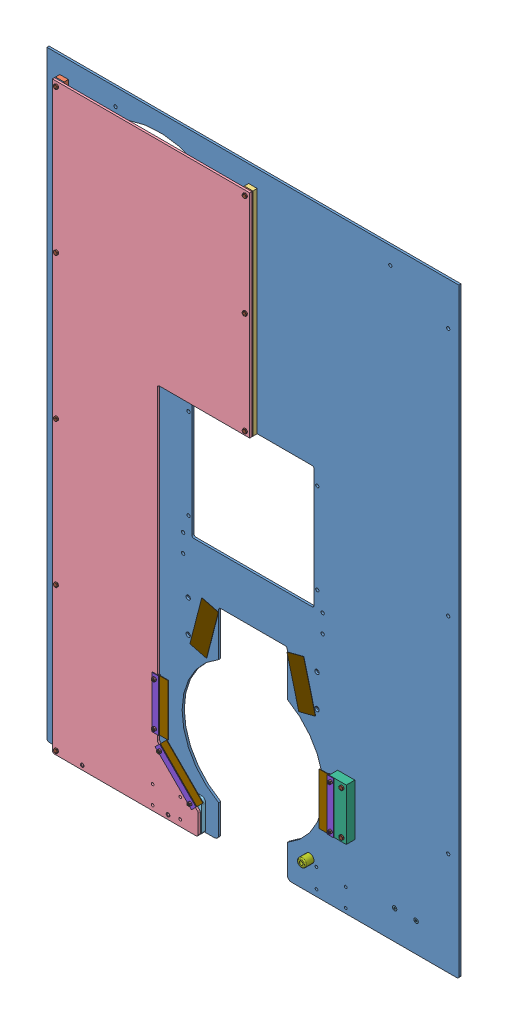
SolidWorks assembly GE-19137, configuration Default. Lengths in mm.
Overall size (1219.2 1778 85.73).
70 component instances, 22 part files, 140 mates.
Components (placement in the parent):
- GE-19131-1: GE-19131 [Default] at origin size (1219.2 1778 6.35)
- GE-19134-1: GE-19134 [Default] at (38.1 0 6.35) size (25.4 1727.2 12.7)
- GE-19135-1: GE-19135 [Default] at (622.3 1098.55 6.35) size (25.4 628.65 12.7)
- GE-19133-2: GE-19133 [Default] at (38.1 0 22.225) size (584.2 1727.2 6.35)
- GE-19138-1: GE-19138 [Default] at (0 0 6.35) size (406.4 120.65 12.7)
- GE-19139-2: GE-19139 [Default] at (1216.025 38.1 31.75) x (-1 0 0) z (0 0 -1) size (50.8 152.4 25.4)
- GE-19140-1: GE-19140 [Default] at (777.6052 88.9 6.35) x (-1 0 0) z (0 0 1) size (25.4 25.4 25.4)
- GE-19190-1: GE-19190 [Default] at (838.1961 325.1694 81.6653) x (0 0 1) z (0 -1 0) size (6.35 44.45 152.4)
  - GE-19190-1-1: GE-19190-1 [Default] at (-48.3278 -36.5164 -30.4306) size (6.35 19.05 152.4)
  - GE-19190-2-1: GE-19190-2 [Default] at (-50.709 -46.4642 60.9432) x (0 0 1) z (-1 0 0) size (152.4 28.57 3.17)
- GE-19190-2: GE-19190 [Default] at (371.4789 233.6306 78.4903) x (0 0 1) z (0 1 0) size (6.35 44.45 152.4)
  - GE-19190-1-1: GE-19190-1 [Default] at (-48.3278 -36.5164 -30.4306) size (6.35 19.05 152.4)
  - GE-19190-2-1: GE-19190-2 [Default] at (-50.709 -46.4642 60.9432) x (0 0 1) z (-1 0 0) size (152.4 28.57 3.17)
- GE-19190-3: GE-19190 [Default] at (455.8906 108.9458 78.4903) x (0 0 1) z (-0.707107 0.707107 0) size (6.35 44.45 152.4)
  - GE-19190-1-1: GE-19190-1 [Default] at (-48.3278 -36.5164 -30.4306) size (6.35 19.05 152.4)
  - GE-19190-2-1: GE-19190-2 [Default] at (-50.709 -46.4642 60.9432) x (0 0 1) z (-1 0 0) size (152.4 28.57 3.17)
- GE-19142-1: GE-19142 [Default] at (114.3 63.5 0) size (88.9 44.45 44.45)
- GE-19142-2: GE-19142 [Default] at (1016 63.5 0) size (88.9 44.45 44.45)
- hex_.25_20_1.5-1: hex_.25_20_1.5 [92865A546] at (50.8 1714.5 11.5094) x (0 0 -1) z (-1 0 0) size (42.07 12.83 11.11)
- hex_.25_20_1.5-2: hex_.25_20_1.5 [92865A546] at (50.8 1289.05 11.5094) x (0 0 -1) z (-0.987351 -0.158553 0) size (42.07 12.83 11.11)
- hex_.25_20_1.5-3: hex_.25_20_1.5 [92865A546] at (50.8 863.6 11.5094) x (0 0 -1) z (-0.959125 -0.282984 0) size (42.07 12.83 11.11)
- hex_.25_20_1.5-4: hex_.25_20_1.5 [92865A546] at (50.8 438.15 11.5094) x (0 0 -1) z (-0.928571 -0.371154 0) size (42.07 12.83 11.11)
- hex_.25_20_1.5-5: hex_.25_20_1.5 [92865A546] at (50.8 12.7 11.5094) x (0 0 -1) z (-0.906989 -0.421154 0) size (42.07 12.83 11.11)
- hex_.25_20_1.5-8: hex_.25_20_1.5 [92865A546] at (898.525 342.9 14.6844) x (0 0 -1) z (-0.985697 -0.168526 0) size (42.07 12.83 11.11)
- hex_.25_20_1.5-9: hex_.25_20_1.5 [92865A546] at (898.525 215.9 14.6844) x (0 0 -1) z (-1 0 0) size (42.07 12.83 11.11)
- hex_.25_20_1.5-10: hex_.25_20_1.5 [92865A546] at (609.6 1714.5 11.5094) x (0 0 -1) z (-0.985697 0.168526 0) size (42.07 12.83 11.11)
- hex_.25_20_1.5-11: hex_.25_20_1.5 [92865A546] at (609.6 1412.875 11.5094) x (0 0 -1) z (-0.952324 0.305088 0) size (42.07 12.83 11.11)
- hex_.25_20_1.5-12: hex_.25_20_1.5 [92865A546] at (609.6 1111.25 11.5094) x (0 0 -1) z (-0.919615 0.39282 0) size (42.07 12.83 11.11)
- nylock_.25_20-1: nylock_.25_20 [Default] at (50.8 1714.5 0) x (-1 0 0) z (0 -1 0) size (11.11 7.94 12.83)
- nylock_.25_20-2: nylock_.25_20 [Default] at (50.8 1289.05 0) x (-0.987351 -0.158553 0) z (0.158553 -0.987351 0) size (11.11 7.94 12.83)
- nylock_.25_20-3: nylock_.25_20 [Default] at (50.8 863.6 0) x (-0.959125 -0.282984 0) z (0.282984 -0.959125 0) size (11.11 7.94 12.83)
- nylock_.25_20-4: nylock_.25_20 [Default] at (50.8 438.15 0) x (-0.928571 -0.371154 0) z (0.371154 -0.928571 0) size (11.11 7.94 12.83)
- nylock_.25_20-5: nylock_.25_20 [Default] at (50.8 12.7 0) x (-0.906989 -0.421154 0) z (0.421154 -0.906989 0) size (11.11 7.94 12.83)
- nylock_.25_20-8: nylock_.25_20 [Default] at (609.6 1714.5 0) x (-0.952324 -0.305088 0) z (0.305088 -0.952324 0) size (11.11 7.94 12.83)
- nylock_.25_20-9: nylock_.25_20 [Default] at (609.6 1412.875 0) x (-0.985697 -0.168526 0) z (0.168526 -0.985697 0) size (11.11 7.94 12.83)
- nylock_.25_20-10: nylock_.25_20 [Default] at (609.6 1111.25 0) x (-1 0 0) z (0 -1 0) size (11.11 7.94 12.83)
- nylock_.25_20-11: nylock_.25_20 [Default] at (898.525 342.9 0) x (-0.985697 0.168526 0) z (-0.168526 -0.985697 0) size (11.11 7.94 12.83)
- nylock_.25_20-12: nylock_.25_20 [Default] at (898.525 215.9 0) x (-0.952324 0.305088 0) z (-0.305088 -0.952324 0) size (11.11 7.94 12.83)
- nylock_10_32-7: nylock_10_32 [90631A411] at (342.9 342.9 30.1625) x (-0.98095 0.194258 0) z (0.194258 0.98095 0) size (9.53 5.95 11)
- nylock_10_32-8: nylock_10_32 [90631A411] at (342.9 215.9 30.1625) x (-0.999342 0.036269 0) z (0.036269 0.999342 0) size (9.53 5.95 11)
- nylock_10_32-3: nylock_10_32 [90631A411] at (358.4172 166.0026 30.1625) x (-0.995826 -0.091275 0) z (-0.091275 0.995826 0) size (9.53 5.95 11)
- nylock_10_32-4: nylock_10_32 [90631A411] at (448.2197 76.2 30.1625) x (-0.982982 -0.183701 0) z (-0.183701 0.982982 0) size (9.53 5.95 11)
- nylock_10_32-9: nylock_10_32 [90631A411] at (866.775 342.9 33.3375) x (-0.971524 -0.236941 0) z (-0.236941 0.971524 0) size (9.53 5.95 11)
- nylock_10_32-6: nylock_10_32 [90631A411] at (866.775 215.9 33.3375) x (-0.969173 -0.24638 0) z (-0.24638 0.969173 0) size (9.53 5.95 11)
- nylock_.25_20-13: nylock_.25_20 [Default] at (1092.2 85.725 -1.9812) x (0.972777 -0.231744 0) z (0.231744 0.972777 0) size (11.11 7.94 12.83)
- nylock_.25_20-14: nylock_.25_20 [Default] at (1028.7 85.725 -1.9812) x (0.994367 -0.105992 0) z (0.105992 0.994367 0) size (11.11 7.94 12.83)
- nylock_.25_20-15: nylock_.25_20 [Default] at (190.5 85.725 -1.9812) x (0.999918 -0.012843 0) z (0.012843 0.999918 0) size (11.11 7.94 12.83)
- nylock_.25_20-16: nylock_.25_20 [Default] at (127 85.725 -1.9812) x (0.999134 0.04161 0) z (-0.04161 0.999134 0) size (11.11 7.94 12.83)
- flat_hex_.25_20_1-1: flat_hex_.25_20_1 [91253A542] at (1028.7 85.725 6.35) x (-1 0 0) z (0 0 1) size (13.49 13.49 25.61)
- flat_hex_.25_20_1-2: flat_hex_.25_20_1 [91253A542] at (1092.2 85.725 6.35) x (-0.987351 -0.158553 0) z (0 0 1) size (13.49 13.49 25.61)
- flat_hex_.25_20_1-3: flat_hex_.25_20_1 [91253A542] at (127 85.725 6.35) x (-0.959125 -0.282984 0) z (0 0 1) size (13.49 13.49 25.61)
- flat_hex_.25_20_1-4: flat_hex_.25_20_1 [91253A542] at (190.5 85.725 6.35) x (-0.928571 -0.371154 0) z (0 0 1) size (13.49 13.49 25.61)
- nylock_.25_20-17: nylock_.25_20 [Default] at (777.6052 88.9 0) x (0.972777 -0.231744 0) z (0.231744 0.972777 0) size (11.11 7.94 12.83)
- button_hex_.25_20_1.25-1: button_hex_.25_20_1.25 [Default] at (777.6052 88.9 22.4028) size (11.1 11.1 35.11)
- flat_hex_10_32_.625-1: flat_hex_10_32_.625 [Default] at (342.9 342.9 22.225) x (-0.923728 -0.383049 0) z (0 0 -1) size (10.44 10.44 15.88)
- flat_hex_10_32_.625-2: flat_hex_10_32_.625 [Default] at (342.9 215.9 22.225) x (-0.85131 -0.524663 0) z (0 0 -1) size (10.44 10.44 15.88)
- flat_hex_10_32_.625-3: flat_hex_10_32_.625 [Default] at (358.4172 166.0026 22.225) x (-0.777574 -0.628792 0) z (0 0 -1) size (10.44 10.44 15.88)
- flat_hex_10_32_.625-4: flat_hex_10_32_.625 [Default] at (448.2197 76.2 22.225) x (-0.715577 -0.698533 0) z (0 0 -1) size (10.44 10.44 15.88)
- flat_hex_10_32_1.375-1: flat_hex_10_32_1.375 [Default] at (866.775 342.9 6.35) x (-0.923728 -0.383049 0) z (0 0 -1) size (10.44 10.44 34.93)
- flat_hex_10_32_1.375-2: flat_hex_10_32_1.375 [Default] at (866.775 215.9 6.35) x (-0.85131 -0.524663 0) z (0 0 -1) size (10.44 10.44 34.93)
- VisionTape-1: VisionTape [Default] at (423.8881 461.6361 6.35) x (0.968246 -0.25 0) z (0 0 1) size (50.8 139.7 0.79)
- VisionTape-2: VisionTape [Default] at (746.125 448.9361 6.35) x (0.968246 0.25 0) z (0 0 1) size (50.8 139.7 0.79)
- GE-19251-1: GE-19251 [Default] at (38.1 0 19.05) size (25.4 1727.2 3.17)
- GE-19252-1: GE-19252 [Default] at (622.3 1098.55 19.05) size (25.4 628.65 3.17)
- GE-19253-1: GE-19253 [92805K33] at (127 12.7 3.175) x (1 0 0) z (0 -1 0) size (7.81 25.4 7.81)
- GE-19253-2: GE-19253 [92805K33] at (381 12.7 3.175) x (1 0 0) z (0 -1 0) size (7.81 25.4 7.81)
- nylock_10_32-10: nylock_10_32 [90631A411] at (127 12.7 0) x (-0.923728 -0.383049 0) z (0.383049 -0.923728 0) size (9.53 5.95 11)
- nylock_10_32-11: nylock_10_32 [90631A411] at (381 12.7 0) x (1 0 0) z (0 1 0) size (9.53 5.95 11)
- round_hex_flange_10_32_1.5_partial-1: round_hex_flange_10_32_1.5_partial [Default] at (127 12.7 31.1404) size (10.34 10.34 40.67)
- round_hex_flange_10_32_1.5_partial-2: round_hex_flange_10_32_1.5_partial [Default] at (381 12.7 31.1404) size (10.34 10.34 40.67)
Mates (geometry in assembly coordinates):
- Coincident1: coincident: plane of GE-19131-1 through (0 0 6.35) normal (0 0 1); plane of GE-19134-1 through (38.1 0 6.35) normal (0 0 -1)
- Concentric1: concentric: cylinder of GE-19131-1 through (50.8 12.7 0) axis (0 0 1) radius 3.3655; cylinder of GE-19134-1 through (50.8 12.7 6.35) axis (0 0 1) radius 3.3655
- Coincident2: coincident: plane of GE-19131-1 through (0 0 6.35) normal (0 0 1); plane of GE-19135-1 through (622.3 1098.55 6.35) normal (0 0 -1)
- Concentric2: concentric: cylinder of GE-19131-1 through (609.6 1111.25 0) axis (0 0 1) radius 3.429; cylinder of GE-19135-1 through (609.6 1111.25 6.35) axis (0 0 1) radius 3.3655
- Coincident3: coincident: plane of assembly; plane of assembly; plane of GE-19133-2 through (38.1 0 22.225) normal (0 0 -1); plane of GE-19251-1 through (38.1 0 22.225) normal (0 0 1)
- Concentric3: concentric: cylinder of assembly; cylinder of assembly; cylinder of GE-19135-1 through (609.6 1714.5 6.35) axis (0 0 1) radius 3.3655; cylinder of GE-19133-2 through (609.6 1714.5 28.575) axis (0 0 1) radius 3.3782
- Concentric4: concentric: cylinder of assembly; cylinder of assembly; cylinder of GE-19134-1 through (50.8 1714.5 6.35) axis (0 0 1) radius 3.3655; cylinder of GE-19133-2 through (50.8 1714.5 28.575) axis (0 0 1) radius 3.3782
- Coincident4: coincident: plane of GE-19131-1 through (0 0 6.35) normal (0 0 1); plane of GE-19138-1 through (457.2 76.2 6.35) normal (0 0 -1)
- Concentric5: concentric: cylinder of GE-19131-1 through (381 12.7 0) axis (0 0 1) radius 3.9688; cylinder of GE-19138-1 through (381 12.7 6.35) axis (0 0 1) radius 3.9688
- Concentric6: concentric: cylinder of GE-19131-1 through (127 12.7 0) axis (0 0 1) radius 3.9688; cylinder of GE-19138-1 through (127 12.7 6.35) axis (0 0 1) radius 3.9688
- Coincident7: coincident: plane of GE-19131-1 through (0 0 6.35) normal (0 0 1); plane of GE-19139-2 through (1216.025 38.1 6.35) normal (0 0 -1)
- Concentric7: concentric: cylinder of GE-19131-1 through (898.525 342.9 0) axis (0 0 1) radius 3.3782; cylinder of GE-19139-2 through (898.525 342.9 6.35) axis (0 0 1) radius 3.3782
- Concentric8: concentric: cylinder of GE-19131-1 through (898.525 215.9 0) axis (0 0 1) radius 3.3782; cylinder of GE-19139-2 through (898.525 215.9 6.35) axis (0 0 1) radius 3.3782
- Coincident8: coincident: plane of GE-19131-1 through (0 0 6.35) normal (0 0 1); plane of GE-19140-1 through (777.6052 88.9 6.35) normal (0 0 -1)
- Concentric9: concentric: cylinder of GE-19131-1 through (777.6052 88.9 0) axis (0 0 1) radius 3.3782; cylinder of GE-19140-1 through (777.6052 88.9 31.75) axis (0 0 -1) radius 3.5719
- Coincident9: coincident: plane of GE-19139-2 through (1216.025 38.1 31.75) normal (0 0 1); plane of GE-19190-1/GE-19190-1-1 through (860.425 203.2 31.75) normal (0 0 -1)
- Concentric10: concentric: cylinder of GE-19139-2 through (866.775 215.9 6.35) axis (0 0 -1) radius 2.8067; cylinder of GE-19190-1/GE-19190-1-1 through (866.775 215.9 33.3375) axis (0 0 -1) radius 2.5797
- Concentric11: concentric: cylinder of GE-19139-2 through (866.775 342.9 6.35) axis (0 0 -1) radius 2.8067; cylinder of GE-19190-1/GE-19190-1-1 through (866.775 342.9 33.3375) axis (0 0 -1) radius 2.5797
- Coincident10: coincident: plane of GE-19133-2 through (38.1 0 28.575) normal (0 0 1); plane of GE-19190-2/GE-19190-1-1 through (349.25 355.6 28.575) normal (0 0 -1)
- Concentric12: concentric: cylinder of GE-19133-2 through (342.9 342.9 22.225) axis (0 0 -1) radius 2.8067; cylinder of GE-19190-2/GE-19190-1-1 through (342.9 342.9 30.1625) axis (0 0 -1) radius 2.5797
- Concentric13: concentric: cylinder of GE-19133-2 through (342.9 215.9 22.225) axis (0 0 -1) radius 2.8067; cylinder of GE-19190-2/GE-19190-1-1 through (342.9 215.9 30.1625) axis (0 0 -1) radius 2.5797
- Coincident11: coincident: plane of GE-19133-2 through (38.1 0 28.575) normal (0 0 1); plane of GE-19190-3/GE-19190-1-1 through (353.9271 179.4729 28.575) normal (0 0 -1)
- Concentric14: concentric: cylinder of GE-19190-3/GE-19190-1-1 through (448.2197 76.2 30.1625) axis (0 0 -1) radius 2.5797; cylinder of GE-19133-2 through (448.2197 76.2 22.225) axis (0 0 -1) radius 2.8067
- Concentric15: concentric: cylinder of GE-19133-2 through (358.4172 166.0026 22.225) axis (0 0 -1) radius 2.8067; cylinder of GE-19190-3/GE-19190-1-1 through (358.4172 166.0026 30.1625) axis (0 0 -1) radius 2.5797
- Coincident12: coincident: plane of GE-19131-1 through (0 0 0) normal (0 0 -1); plane of GE-19142-1 through (203.2 107.95 0) normal (0 0 1)
- Concentric16: concentric: cylinder of GE-19131-1 through (127 85.725 6.35) axis (0 0 1) radius 3.5712; cylinder of GE-19142-1 through (127 85.725 -88.9) axis (0 0 1) radius 3.3782
- Coincident13: coincident: plane of GE-19131-1 through (0 0 0) normal (0 0 -1); plane of GE-19142-2 through (1104.9 107.95 0) normal (0 0 1)
- Concentric17: concentric: cylinder of GE-19131-1 through (1028.7 85.725 6.35) axis (0 0 1) radius 3.5712; cylinder of GE-19142-2 through (1028.7 85.725 -88.9) axis (0 0 1) radius 3.3782
- Concentric18: concentric: cylinder of GE-19131-1 through (1092.2 85.725 6.35) axis (0 0 1) radius 3.5712; cylinder of GE-19142-2 through (1092.2 85.725 -88.9) axis (0 0 1) radius 3.3782
- Coincident14: coincident: plane of assembly; plane of assembly; plane of GE-19133-2 through (38.1 0 28.575) normal (0 0 1); plane of hex_.25_20_1.5-1 through (45.2437 1711.2921 28.575) normal (0 0 -1)
- Concentric19: concentric: cylinder of assembly; cylinder of assembly; cylinder of GE-19133-2 through (50.8 1714.5 28.575) axis (0 0 1) radius 3.3782; cylinder of hex_.25_20_1.5-1 through (50.8 1714.5 28.575) axis (0 0 -1) radius 3.175
- Concentric20: concentric: cylinder of assembly; cylinder of assembly; cylinder of hex_.25_20_1.5-1 through (50.8 1714.5 28.575) axis (0 0 -1) radius 3.175; cylinder of nylock_.25_20-1 through (50.8 1714.5 0) axis (0 0 -1) radius 3.175
- Coincident15: coincident: plane of assembly; plane of assembly; plane of GE-19133-2 through (38.1 0 28.575) normal (0 0 1); plane of hex_.25_20_1.5-2 through (45.8227 1285.0017 28.575) normal (0 0 -1)
- Concentric21: concentric: cylinder of assembly; cylinder of assembly; cylinder of GE-19133-2 through (50.8 1289.05 28.575) axis (0 0 1) radius 3.3782; cylinder of hex_.25_20_1.5-2 through (50.8 1289.05 28.575) axis (0 0 -1) radius 3.175
- Concentric22: concentric: cylinder of assembly; cylinder of assembly; cylinder of hex_.25_20_1.5-2 through (50.8 1289.05 28.575) axis (0 0 -1) radius 3.175; cylinder of nylock_.25_20-2 through (50.8 1289.05 0) axis (0 0 -1) radius 3.175
- Coincident16: coincident: plane of assembly; plane of assembly; plane of GE-19133-2 through (38.1 0 28.575) normal (0 0 1); plane of hex_.25_20_1.5-3 through (46.3786 858.9509 28.575) normal (0 0 -1)
- Concentric23: concentric: cylinder of assembly; cylinder of assembly; cylinder of GE-19133-2 through (50.8 863.6 28.575) axis (0 0 1) radius 3.3782; cylinder of hex_.25_20_1.5-3 through (50.8 863.6 28.575) axis (0 0 -1) radius 3.175
- Concentric24: concentric: cylinder of assembly; cylinder of assembly; cylinder of hex_.25_20_1.5-3 through (50.8 863.6 28.575) axis (0 0 -1) radius 3.175; cylinder of nylock_.25_20-3 through (50.8 863.6 0) axis (0 0 -1) radius 3.175
- Coincident17: coincident: plane of assembly; plane of assembly; plane of GE-19133-2 through (38.1 0 28.575) normal (0 0 1); plane of hex_.25_20_1.5-4 through (46.8312 433.109 28.575) normal (0 0 -1)
- Concentric25: concentric: cylinder of assembly; cylinder of assembly; cylinder of GE-19133-2 through (50.8 438.15 28.575) axis (0 0 1) radius 3.3782; cylinder of hex_.25_20_1.5-4 through (50.8 438.15 28.575) axis (0 0 -1) radius 3.175
- Concentric26: concentric: cylinder of assembly; cylinder of assembly; cylinder of hex_.25_20_1.5-4 through (50.8 438.15 28.575) axis (0 0 -1) radius 3.175; cylinder of nylock_.25_20-4 through (50.8 438.15 0) axis (0 0 -1) radius 3.175
- Coincident18: coincident: plane of assembly; plane of assembly; plane of GE-19133-2 through (38.1 0 28.575) normal (0 0 1); plane of hex_.25_20_1.5-5 through (47.1116 7.4504 28.575) normal (0 0 -1)
- Concentric27: concentric: cylinder of assembly; cylinder of assembly; cylinder of GE-19133-2 through (50.8 12.7 28.575) axis (0 0 1) radius 3.3782; cylinder of hex_.25_20_1.5-5 through (50.8 12.7 28.575) axis (0 0 -1) radius 3.175
- Concentric28: concentric: cylinder of assembly; cylinder of assembly; cylinder of hex_.25_20_1.5-5 through (50.8 12.7 28.575) axis (0 0 -1) radius 3.175; cylinder of nylock_.25_20-5 through (50.8 12.7 0) axis (0 0 -1) radius 3.175
- Coincident22: coincident: plane of assembly; plane of assembly; plane of GE-19139-2 through (1216.025 38.1 31.75) normal (0 0 1); plane of hex_.25_20_1.5-8 through (893.5888 338.8016 31.75) normal (0 0 -1)
- Concentric33: concentric: cylinder of assembly; cylinder of assembly; cylinder of GE-19139-2 through (898.525 342.9 6.35) axis (0 0 1) radius 3.3782; cylinder of hex_.25_20_1.5-8 through (898.525 342.9 31.75) axis (0 0 -1) radius 3.175
- Concentric34: concentric: cylinder of assembly; cylinder of assembly; cylinder of hex_.25_20_1.5-8 through (898.525 342.9 31.75) axis (0 0 -1) radius 3.175; cylinder of nylock_.25_20-11 through (898.525 342.9 0) axis (0 0 -1) radius 3.175
- Coincident23: coincident: plane of assembly; plane of assembly; plane of GE-19139-2 through (1216.025 38.1 31.75) normal (0 0 1); plane of hex_.25_20_1.5-9 through (892.9688 212.6921 31.75) normal (0 0 -1)
- Concentric35: concentric: cylinder of assembly; cylinder of assembly; cylinder of GE-19139-2 through (898.525 215.9 6.35) axis (0 0 1) radius 3.3782; cylinder of hex_.25_20_1.5-9 through (898.525 215.9 31.75) axis (0 0 -1) radius 3.175
- Concentric36: concentric: cylinder of assembly; cylinder of assembly; cylinder of hex_.25_20_1.5-9 through (898.525 215.9 31.75) axis (0 0 -1) radius 3.175; cylinder of nylock_.25_20-12 through (898.525 215.9 0) axis (0 0 -1) radius 3.175
- Coincident24: coincident: plane of assembly; plane of assembly; plane of GE-19133-2 through (38.1 0 28.575) normal (0 0 1); plane of hex_.25_20_1.5-10 through (603.5826 1712.2744 28.575) normal (0 0 -1)
- Concentric37: concentric: cylinder of assembly; cylinder of assembly; cylinder of GE-19133-2 through (609.6 1714.5 28.575) axis (0 0 1) radius 3.3782; cylinder of hex_.25_20_1.5-10 through (609.6 1714.5 28.575) axis (0 0 -1) radius 3.175
- Concentric38: concentric: cylinder of assembly; cylinder of assembly; cylinder of hex_.25_20_1.5-10 through (609.6 1714.5 28.575) axis (0 0 -1) radius 3.175; cylinder of nylock_.25_20-8 through (609.6 1714.5 0) axis (0 0 -1) radius 3.175
- Coincident25: coincident: plane of assembly; plane of assembly; plane of GE-19133-2 through (38.1 0 28.575) normal (0 0 1); plane of hex_.25_20_1.5-11 through (603.33 1411.5152 28.575) normal (0 0 -1)
- Concentric39: concentric: cylinder of assembly; cylinder of assembly; cylinder of GE-19133-2 through (609.6 1412.875 28.575) axis (0 0 1) radius 3.3782; cylinder of hex_.25_20_1.5-11 through (609.6 1412.875 28.575) axis (0 0 -1) radius 3.175
- Concentric40: concentric: cylinder of assembly; cylinder of assembly; cylinder of hex_.25_20_1.5-11 through (609.6 1412.875 28.575) axis (0 0 -1) radius 3.175; cylinder of nylock_.25_20-9 through (609.6 1412.875 0) axis (0 0 -1) radius 3.175
- Coincident26: coincident: plane of assembly; plane of assembly; plane of GE-19133-2 through (38.1 0 28.575) normal (0 0 1); plane of hex_.25_20_1.5-12 through (603.2303 1110.4826 28.575) normal (0 0 -1)
- Concentric41: concentric: cylinder of assembly; cylinder of assembly; cylinder of GE-19133-2 through (609.6 1111.25 28.575) axis (0 0 1) radius 3.3782; cylinder of hex_.25_20_1.5-12 through (609.6 1111.25 28.575) axis (0 0 -1) radius 3.175
- Concentric42: concentric: cylinder of assembly; cylinder of assembly; cylinder of hex_.25_20_1.5-12 through (609.6 1111.25 28.575) axis (0 0 -1) radius 3.175; cylinder of nylock_.25_20-10 through (609.6 1111.25 0) axis (0 0 -1) radius 3.175
- Coincident29: coincident: plane of GE-19131-1 through (0 0 0) normal (0 0 -1); plane of nylock_.25_20-1 through (50.8 1714.5 0) normal (0 0 1)
- Coincident30: coincident: plane of GE-19131-1 through (0 0 0) normal (0 0 -1); plane of nylock_.25_20-2 through (50.8 1289.05 0) normal (0 0 1)
- Coincident31: coincident: plane of GE-19131-1 through (0 0 0) normal (0 0 -1); plane of nylock_.25_20-3 through (50.8 863.6 0) normal (0 0 1)
- Coincident32: coincident: plane of GE-19131-1 through (0 0 0) normal (0 0 -1); plane of nylock_.25_20-4 through (50.8 438.15 0) normal (0 0 1)
- Coincident33: coincident: plane of GE-19131-1 through (0 0 0) normal (0 0 -1); plane of nylock_.25_20-5 through (50.8 12.7 0) normal (0 0 1)
- Coincident36: coincident: plane of GE-19131-1 through (0 0 0) normal (0 0 -1); plane of nylock_.25_20-8 through (609.6 1714.5 0) normal (0 0 1)
- Coincident37: coincident: plane of GE-19131-1 through (0 0 0) normal (0 0 -1); plane of nylock_.25_20-9 through (609.6 1412.875 0) normal (0 0 1)
- Coincident38: coincident: plane of GE-19131-1 through (0 0 0) normal (0 0 -1); plane of nylock_.25_20-10 through (609.6 1111.25 0) normal (0 0 1)
- Coincident39: coincident: plane of GE-19131-1 through (0 0 0) normal (0 0 -1); plane of nylock_.25_20-11 through (898.525 342.9 0) normal (0 0 1)
- Coincident40: coincident: plane of GE-19131-1 through (0 0 0) normal (0 0 -1); plane of nylock_.25_20-12 through (898.525 215.9 0) normal (0 0 1)
- Concentric43: concentric: cylinder of GE-19190-2/GE-19190-1-1 through (342.9 342.9 30.1625) axis (0 0 -1) radius 2.5797; cylinder of nylock_10_32-7 through (342.9 342.9 35.1996) axis (0 0 -1) radius 2.0454
- Coincident42: coincident: plane of GE-19190-2/GE-19190-1-1 through (354.0125 355.6 30.1625) normal (0 0 1); plane of nylock_10_32-7 through (341.8317 337.5055 30.1625) normal (0 0 -1)
- Concentric44: concentric: cylinder of assembly; cylinder of assembly; cylinder of nylock_10_32-7 through (342.9 342.9 35.1996) axis (0 0 -1) radius 2.0454; cylinder of flat_hex_10_32_.625-1 through (342.9 342.9 22.225) axis (0 0 -1) radius 5.2197
- Coincident43: coincident: plane of GE-19190-2/GE-19190-1-1 through (354.0125 355.6 30.1625) normal (0 0 1); plane of nylock_10_32-8 through (342.7005 210.4044 30.1625) normal (0 0 -1)
- Concentric45: concentric: cylinder of GE-19190-2/GE-19190-1-1 through (342.9 215.9 30.1625) axis (0 0 -1) radius 2.5797; cylinder of nylock_10_32-8 through (342.9 215.9 35.1996) axis (0 0 -1) radius 2.0454
- Concentric46: concentric: cylinder of assembly; cylinder of assembly; cylinder of nylock_10_32-8 through (342.9 215.9 35.1996) axis (0 0 -1) radius 2.0454; cylinder of flat_hex_10_32_.625-2 through (342.9 215.9 22.225) axis (0 0 -1) radius 5.2197
- Coincident44: coincident: plane of GE-19190-2/GE-19190-1-1 through (354.0125 355.6 30.1625) normal (0 0 1); plane of nylock_10_32-3 through (358.9191 160.5263 30.1625) normal (0 0 -1)
- Concentric47: concentric: cylinder of GE-19190-3/GE-19190-1-1 through (358.4172 166.0026 30.1625) axis (0 0 -1) radius 2.5797; cylinder of nylock_10_32-3 through (358.4172 166.0026 35.1996) axis (0 0 -1) radius 2.0454
- Concentric48: concentric: cylinder of assembly; cylinder of assembly; cylinder of nylock_10_32-3 through (358.4172 166.0026 35.1996) axis (0 0 -1) radius 2.0454; cylinder of flat_hex_10_32_.625-3 through (358.4172 166.0026 22.225) axis (0 0 -1) radius 5.2197
- Coincident45: coincident: plane of GE-19190-2/GE-19190-1-1 through (354.0125 355.6 30.1625) normal (0 0 1); plane of nylock_10_32-4 through (449.23 70.7943 30.1625) normal (0 0 -1)
- Concentric49: concentric: cylinder of GE-19190-3/GE-19190-1-1 through (448.2197 76.2 30.1625) axis (0 0 -1) radius 2.5797; cylinder of nylock_10_32-4 through (448.2197 76.2 35.1996) axis (0 0 -1) radius 2.0454
- Concentric50: concentric: cylinder of assembly; cylinder of assembly; cylinder of nylock_10_32-4 through (448.2197 76.2 35.1996) axis (0 0 -1) radius 2.0454; cylinder of flat_hex_10_32_.625-4 through (448.2197 76.2 22.225) axis (0 0 -1) radius 5.2197
- Concentric51: concentric: cylinder of GE-19190-1/GE-19190-1-1 through (866.775 342.9 33.3375) axis (0 0 -1) radius 2.5797; cylinder of nylock_10_32-9 through (866.775 342.9 38.3746) axis (0 0 -1) radius 2.0454
- Coincident47: coincident: plane of GE-19190-1/GE-19190-1-1 through (855.6625 203.2 33.3375) normal (0 0 1); plane of nylock_10_32-9 through (868.078 337.5573 33.3375) normal (0 0 -1)
- Concentric52: concentric: cylinder of nylock_10_32-9 through (866.775 342.9 38.3746) axis (0 0 -1) radius 2.0454; cylinder of flat_hex_10_32_1.375-1 through (866.775 342.9 6.35) axis (0 0 -1) radius 5.2197
- Concentric53: concentric: cylinder of GE-19190-1/GE-19190-1-1 through (866.775 215.9 33.3375) axis (0 0 -1) radius 2.5797; cylinder of nylock_10_32-6 through (866.775 215.9 38.3746) axis (0 0 -1) radius 2.0454
- Coincident49: coincident: plane of GE-19190-1/GE-19190-1-1 through (855.6625 203.2 33.3375) normal (0 0 1); plane of nylock_10_32-6 through (868.1299 210.5703 33.3375) normal (0 0 -1)
- Concentric54: concentric: cylinder of nylock_10_32-6 through (866.775 215.9 38.3746) axis (0 0 -1) radius 2.0454; cylinder of flat_hex_10_32_1.375-2 through (866.775 215.9 6.35) axis (0 0 -1) radius 5.2197
- Coincident50: coincident: plane of assembly; plane of assembly; plane of GE-19142-2 through (1104.9 65.4812 -1.9812) normal (0 0 -1); plane of nylock_.25_20-13 through (1092.2 85.725 -1.9812) normal (0 0 1)
- Concentric55: concentric: cylinder of assembly; cylinder of assembly; cylinder of GE-19142-2 through (1092.2 85.725 -88.9) axis (0 0 1) radius 3.3782; cylinder of nylock_.25_20-13 through (1092.2 85.725 -1.9812) axis (0 0 -1) radius 3.175
- Coincident51: coincident: plane of assembly; plane of assembly; plane of GE-19142-2 through (1104.9 65.4812 -1.9812) normal (0 0 -1); plane of nylock_.25_20-14 through (1028.7 85.725 -1.9812) normal (0 0 1)
- Concentric56: concentric: cylinder of assembly; cylinder of assembly; cylinder of GE-19142-2 through (1028.7 85.725 -88.9) axis (0 0 1) radius 3.3782; cylinder of nylock_.25_20-14 through (1028.7 85.725 -1.9812) axis (0 0 -1) radius 3.175
- Coincident52: coincident: plane of GE-19142-1 through (203.2 65.4812 -1.9812) normal (0 0 -1); plane of nylock_.25_20-15 through (190.5 85.725 -1.9812) normal (0 0 1)
- Concentric57: concentric: cylinder of GE-19142-1 through (190.5 85.725 -88.9) axis (0 0 1) radius 3.3782; cylinder of nylock_.25_20-15 through (190.5 85.725 -1.9812) axis (0 0 -1) radius 3.175
- Coincident53: coincident: plane of GE-19142-1 through (203.2 65.4812 -1.9812) normal (0 0 -1); plane of nylock_.25_20-16 through (127 85.725 -1.9812) normal (0 0 1)
- Concentric58: concentric: cylinder of GE-19142-1 through (127 85.725 -88.9) axis (0 0 1) radius 3.3782; cylinder of nylock_.25_20-16 through (127 85.725 -1.9812) axis (0 0 -1) radius 3.175
- Coincident54: coincident: plane of GE-19131-1 through (0 0 6.35) normal (0 0 1); plane of flat_hex_.25_20_1-1 through (1028.7 88.9 6.35) normal (0 0 1)
- Concentric59: concentric: cylinder of GE-19142-2 through (1028.7 85.725 -88.9) axis (0 0 1) radius 3.3782; cylinder of flat_hex_.25_20_1-1 through (1028.7 85.725 -19.05) axis (0 0 -1) radius 3.175
- Coincident55: coincident: plane of GE-19131-1 through (0 0 6.35) normal (0 0 1); plane of flat_hex_.25_20_1-2 through (1091.6966 88.8598 6.35) normal (0 0 1)
- Concentric60: concentric: cylinder of GE-19142-2 through (1092.2 85.725 -88.9) axis (0 0 1) radius 3.3782; cylinder of flat_hex_.25_20_1-2 through (1092.2 85.725 -19.05) axis (0 0 -1) radius 3.175
- Coincident56: coincident: plane of GE-19131-1 through (0 0 6.35) normal (0 0 1); plane of flat_hex_.25_20_1-3 through (126.1015 88.7702 6.35) normal (0 0 1)
- Concentric61: concentric: cylinder of GE-19142-1 through (127 85.725 -88.9) axis (0 0 1) radius 3.3782; cylinder of flat_hex_.25_20_1-3 through (127 85.725 -19.05) axis (0 0 -1) radius 3.175
- Coincident57: coincident: plane of GE-19131-1 through (0 0 6.35) normal (0 0 1); plane of flat_hex_.25_20_1-4 through (189.3216 88.6732 6.35) normal (0 0 1)
- Concentric62: concentric: cylinder of GE-19142-1 through (190.5 85.725 -88.9) axis (0 0 1) radius 3.3782; cylinder of flat_hex_.25_20_1-4 through (190.5 85.725 -19.05) axis (0 0 -1) radius 3.175
- Coincident59: coincident: plane of GE-19131-1 through (0 0 0) normal (0 0 -1); plane of nylock_.25_20-17 through (777.6052 88.9 0) normal (0 0 1)
- Concentric63: concentric: cylinder of GE-19131-1 through (777.6052 88.9 0) axis (0 0 1) radius 3.3782; cylinder of nylock_.25_20-17 through (777.6052 88.9 0) axis (0 0 -1) radius 3.175
- Coincident61: coincident: plane of assembly; plane of assembly; plane of GE-19140-1 through (777.6052 88.9 19.05) normal (0 0 1); plane of button_hex_.25_20_1.25-1 through (777.6052 83.3501 19.05) normal (0 0 -1)
- Concentric64: concentric: cylinder of GE-19140-1 through (777.6052 88.9 19.05) axis (0 0 1) radius 5.5563; cylinder of button_hex_.25_20_1.25-1 through (777.6052 88.9 22.4028) axis (0 0 1) radius 5.5499
- Coincident62: coincident: plane of assembly; plane of assembly; plane of GE-19133-2 through (38.1 0 22.225) normal (0 0 -1); plane of flat_hex_10_32_.625-3 through (359.9345 164.1263 22.225) normal (0 0 -1)
- Coincident63: coincident: plane of assembly; plane of assembly; plane of GE-19133-2 through (38.1 0 22.225) normal (0 0 -1); plane of flat_hex_10_32_.625-1 through (343.8243 340.671 22.225) normal (0 0 -1)
- Coincident64: coincident: plane of assembly; plane of assembly; plane of GE-19133-2 through (38.1 0 22.225) normal (0 0 -1); plane of flat_hex_10_32_.625-1 through (343.8243 340.671 22.225) normal (0 0 -1)
- Coincident65: coincident: plane of assembly; plane of assembly; plane of GE-19133-2 through (38.1 0 22.225) normal (0 0 -1); plane of flat_hex_10_32_.625-2 through (344.166 213.8458 22.225) normal (0 0 -1)
- Coincident67: coincident: plane of GE-19139-2 through (1216.025 38.1 6.35) normal (0 0 -1); plane of flat_hex_10_32_1.375-1 through (866.775 342.9 6.35) normal (0 0 -1)
- Coincident68: coincident: plane of GE-19139-2 through (1216.025 38.1 6.35) normal (0 0 -1); plane of flat_hex_10_32_1.375-2 through (866.775 215.9 6.35) normal (0 0 -1)
- Coincident69: coincident: plane of GE-19131-1 through (0 0 6.35) normal (0 0 1); plane of VisionTape-2 through (746.125 448.9361 6.35) normal (0 0 -1)
- Coincident70: coincident: plane of GE-19131-1 through (0 0 6.35) normal (0 0 1); plane of VisionTape-1 through (423.8881 461.6361 6.35) normal (0 0 -1)
- Coincident78: coincident: line of GE-19131-1; line of VisionTape-1 through (508 584.2 7.1437) axis (0 0 -1)
- Coincident79: coincident: plane of GE-19131-1 through (508 596.9 0) normal (0 -1 0); line of VisionTape-1 through (458.8131 596.9 7.1437) axis (0 0 -1)
- Distance3: distance = 12.7 mm: line of VisionTape-1 through (508 584.2 7.1437) axis (0 0 -1); plane of GE-19131-1 through (508 596.9 0) normal (0 -1 0)
- Coincident81: coincident: plane of GE-19131-1 through (711.2 596.9 0) normal (-1 0 0); line of VisionTape-2 through (711.2 584.2 7.1437) axis (0 0 -1)
- Coincident82: coincident: plane of GE-19131-1 through (508 596.9 0) normal (0 -1 0); line of VisionTape-2 through (760.3869 596.9 7.1437) axis (0 0 -1)
- Distance4: distance = 12.7 mm: plane of GE-19131-1 through (508 596.9 0) normal (0 -1 0); line of VisionTape-2 through (711.2 584.2 7.1437) axis (0 0 -1)
- Coincident83: coincident: plane of assembly; plane of assembly; plane of GE-19133-2 through (38.1 0 22.225) normal (0 0 -1); plane of flat_hex_10_32_.625-4 through (449.9053 74.4733 22.225) normal (0 0 -1)
- Coincident84: coincident: plane of assembly; plane of assembly; plane of GE-19134-1 through (38.1 0 19.05) normal (0 0 1); plane of GE-19251-1 through (38.1 0 19.05) normal (0 0 -1)
- Coincident85: coincident: plane of assembly; plane of assembly; plane of GE-19134-1 through (38.1 1727.2 19.05) normal (-1 0 0); plane of GE-19251-1 through (38.1 1727.2 22.225) normal (-1 0 0)
- Coincident86: coincident: plane of assembly; plane of assembly; plane of GE-19134-1 through (38.1 1727.2 19.05) normal (0 1 0); plane of GE-19251-1 through (38.1 1727.2 22.225) normal (0 1 0)
- Coincident88: coincident: plane of assembly; plane of assembly; plane of GE-19135-1 through (622.3 1098.55 19.05) normal (0 0 1); plane of GE-19252-1 through (622.3 1098.55 19.05) normal (0 0 -1)
- Coincident89: coincident: plane of assembly; plane of assembly; plane of GE-19135-1 through (622.3 1098.55 19.05) normal (1 0 0); plane of GE-19252-1 through (622.3 1098.55 22.225) normal (1 0 0)
- Coincident90: coincident: plane of assembly; plane of assembly; plane of GE-19135-1 through (622.3 1727.2 19.05) normal (0 1 0); plane of GE-19252-1 through (622.3 1727.2 22.225) normal (0 1 0)
- Concentric67: concentric: circle of assembly; circle of assembly; circle of GE-19133-2; circle of GE-19253-1
- Coincident95: coincident: plane of GE-19131-1 through (0 0 0) normal (0 0 -1); plane of nylock_10_32-10 through (124.8935 17.7798 0) normal (0 0 1)
- Concentric71: concentric: circle of assembly; circle of assembly; circle of GE-19133-2; circle of GE-19253-2
- Coincident99: coincident: plane of GE-19131-1 through (0 0 0) normal (0 0 -1); plane of nylock_10_32-11 through (381 7.2007 0) normal (0 0 1)
- Concentric73: concentric: circle of assembly; circle of assembly; circle of GE-19253-1; circle of round_hex_flange_10_32_1.5_partial-1
- Coincident100: coincident: plane of assembly; plane of assembly; plane of GE-19133-2 through (38.1 0 28.575) normal (0 0 1); plane of round_hex_flange_10_32_1.5_partial-1 through (127 8.1153 28.575) normal (0 0 -1)
- Concentric74: concentric: circle of assembly; circle of assembly; circle of GE-19253-2; circle of round_hex_flange_10_32_1.5_partial-2
- Coincident101: coincident: plane of assembly; plane of assembly; plane of GE-19253-2 through (377.0947 16.6052 28.575) normal (0 0 1); plane of round_hex_flange_10_32_1.5_partial-2 through (381 8.1153 28.575) normal (0 0 -1)
- Concentric75: concentric: circle of GE-19131-1; circle of nylock_10_32-10
- Concentric76: concentric: circle of GE-19131-1; circle of nylock_10_32-11
- Coincident102: coincident: plane of assembly; plane of assembly; plane of GE-19253-1 through (123.0948 16.6052 28.575) normal (0 0 1); plane of round_hex_flange_10_32_1.5_partial-1 through (127 8.1153 28.575) normal (0 0 -1)
- Coincident103: coincident: plane of assembly; plane of assembly; plane of GE-19133-2 through (38.1 0 28.575) normal (0 0 1); plane of round_hex_flange_10_32_1.5_partial-2 through (381 8.1153 28.575) normal (0 0 -1)
